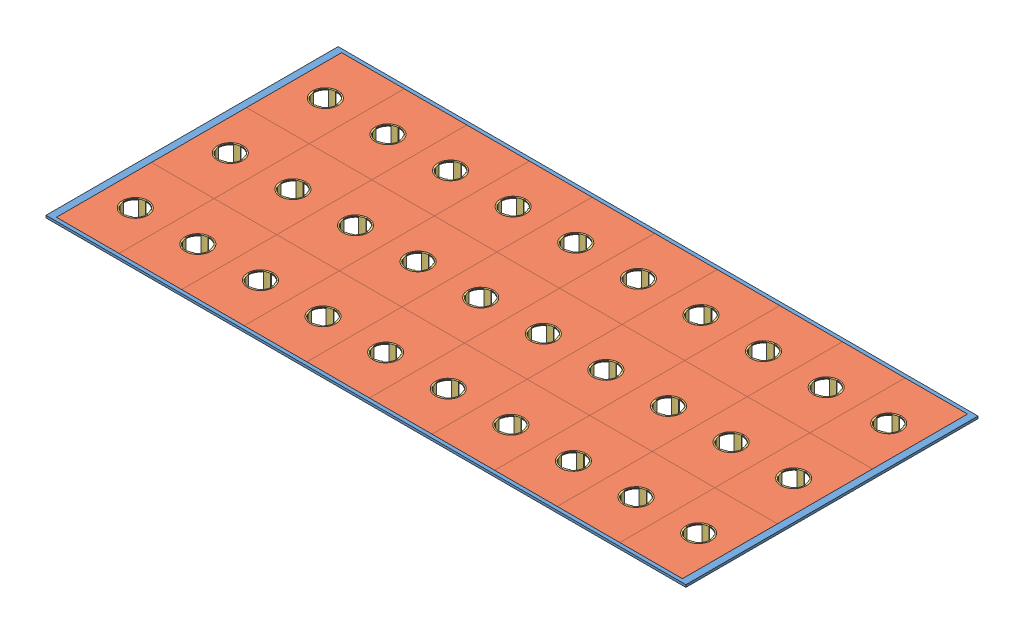
SolidWorks assembly A_Gaveta, configuration Default. Lengths in mm.
Overall size (1104 41 504.01).
61 component instances, 3 part files, 4 mates.
Components (placement in the parent):
- Estrutura_gaveta-2: Estrutura_gaveta [Default] at (152.42 973.7974 512.7504) size (1104 4 504.01)
- Copo_cultura-81: Copo_cultura [Default] at (-333.58 977.7974 348.7504) size (108 2 164)
- Copo_cultura-82: Copo_cultura [Default] at (-225.58 977.7974 348.7504) size (108 2 164)
- Copo_cultura-83: Copo_cultura [Default] at (-117.58 977.7974 348.7504) size (108 2 164)
- Copo_cultura-84: Copo_cultura [Default] at (-9.58 977.7974 348.7504) size (108 2 164)
- Copo_cultura-85: Copo_cultura [Default] at (98.42 977.7974 348.7504) size (108 2 164)
- Copo_cultura-86: Copo_cultura [Default] at (206.42 977.7974 348.7504) size (108 2 164)
- Copo_cultura-87: Copo_cultura [Default] at (314.42 977.7974 348.7504) size (108 2 164)
- Copo_cultura-88: Copo_cultura [Default] at (422.42 977.7974 348.7504) size (108 2 164)
- Copo_cultura-89: Copo_cultura [Default] at (530.42 977.7974 348.7504) size (108 2 164)
- Copo_cultura-90: Copo_cultura [Default] at (638.42 977.7974 348.7504) size (108 2 164)
- Copo_cultura-91: Copo_cultura [Default] at (-333.58 977.7974 512.7504) size (108 2 164)
- Copo_cultura-92: Copo_cultura [Default] at (-333.58 977.7974 676.7504) size (108 2 164)
- Copo_cultura-93: Copo_cultura [Default] at (-225.58 977.7974 512.7504) size (108 2 164)
- Copo_cultura-94: Copo_cultura [Default] at (-225.58 977.7974 676.7504) size (108 2 164)
- Copo_cultura-95: Copo_cultura [Default] at (-117.58 977.7974 512.7504) size (108 2 164)
- Copo_cultura-96: Copo_cultura [Default] at (-117.58 977.7974 676.7504) size (108 2 164)
- Copo_cultura-97: Copo_cultura [Default] at (-9.58 977.7974 512.7504) size (108 2 164)
- Copo_cultura-98: Copo_cultura [Default] at (-9.58 977.7974 676.7504) size (108 2 164)
- Copo_cultura-99: Copo_cultura [Default] at (98.42 977.7974 512.7504) size (108 2 164)
- Copo_cultura-100: Copo_cultura [Default] at (98.42 977.7974 676.7504) size (108 2 164)
- Copo_cultura-101: Copo_cultura [Default] at (206.42 977.7974 512.7504) size (108 2 164)
- Copo_cultura-102: Copo_cultura [Default] at (206.42 977.7974 676.7504) size (108 2 164)
- Copo_cultura-103: Copo_cultura [Default] at (314.42 977.7974 512.7504) size (108 2 164)
- Copo_cultura-104: Copo_cultura [Default] at (314.42 977.7974 676.7504) size (108 2 164)
- Copo_cultura-105: Copo_cultura [Default] at (422.42 977.7974 512.7504) size (108 2 164)
- Copo_cultura-106: Copo_cultura [Default] at (422.42 977.7974 676.7504) size (108 2 164)
- Copo_cultura-107: Copo_cultura [Default] at (530.42 977.7974 512.7504) size (108 2 164)
- Copo_cultura-108: Copo_cultura [Default] at (530.42 977.7974 676.7504) size (108 2 164)
- Copo_cultura-109: Copo_cultura [Default] at (638.42 977.7974 512.7504) size (108 2 164)
- Copo_cultura-110: Copo_cultura [Default] at (638.42 977.7974 676.7504) size (108 2 164)
- Capsula_Cultura-1: Capsula_Cultura [Default] at (-333.58 976.7974 676.7504) x (0.947711 0 -0.319129) z (0.319129 0 0.947711) size (44 41 44)
- Capsula_Cultura-2: Capsula_Cultura [Default] at (-225.58 976.7974 676.7504) x (0.947711 0 -0.319129) z (0.319129 0 0.947711) size (44 41 44)
- Capsula_Cultura-3: Capsula_Cultura [Default] at (-117.58 976.7974 676.7504) x (0.947711 0 -0.319129) z (0.319129 0 0.947711) size (44 41 44)
- Capsula_Cultura-4: Capsula_Cultura [Default] at (-9.58 976.7974 676.7504) x (0.947711 0 -0.319129) z (0.319129 0 0.947711) size (44 41 44)
- Capsula_Cultura-5: Capsula_Cultura [Default] at (98.42 976.7974 676.7504) x (0.947711 0 -0.319129) z (0.319129 0 0.947711) size (44 41 44)
- Capsula_Cultura-6: Capsula_Cultura [Default] at (206.42 976.7974 676.7504) x (0.947711 0 -0.319129) z (0.319129 0 0.947711) size (44 41 44)
- Capsula_Cultura-7: Capsula_Cultura [Default] at (314.42 976.7974 676.7504) x (0.947711 0 -0.319129) z (0.319129 0 0.947711) size (44 41 44)
- Capsula_Cultura-8: Capsula_Cultura [Default] at (422.42 976.7974 676.7504) x (0.947711 0 -0.319129) z (0.319129 0 0.947711) size (44 41 44)
- Capsula_Cultura-9: Capsula_Cultura [Default] at (530.42 976.7974 676.7504) x (0.947711 0 -0.319129) z (0.319129 0 0.947711) size (44 41 44)
- Capsula_Cultura-10: Capsula_Cultura [Default] at (638.42 976.7974 676.7504) x (0.947711 0 -0.319129) z (0.319129 0 0.947711) size (44 41 44)
- Capsula_Cultura-11: Capsula_Cultura [Default] at (-333.58 976.7974 512.7504) x (0.947711 0 -0.319129) z (0.319129 0 0.947711) size (44 41 44)
- Capsula_Cultura-12: Capsula_Cultura [Default] at (-333.58 976.7974 348.7504) x (0.947711 0 -0.319129) z (0.319129 0 0.947711) size (44 41 44)
- Capsula_Cultura-13: Capsula_Cultura [Default] at (-225.58 976.7974 512.7504) x (0.947711 0 -0.319129) z (0.319129 0 0.947711) size (44 41 44)
- Capsula_Cultura-14: Capsula_Cultura [Default] at (-225.58 976.7974 348.7504) x (0.947711 0 -0.319129) z (0.319129 0 0.947711) size (44 41 44)
- Capsula_Cultura-15: Capsula_Cultura [Default] at (-117.58 976.7974 512.7504) x (0.947711 0 -0.319129) z (0.319129 0 0.947711) size (44 41 44)
- Capsula_Cultura-16: Capsula_Cultura [Default] at (-117.58 976.7974 348.7504) x (0.947711 0 -0.319129) z (0.319129 0 0.947711) size (44 41 44)
- Capsula_Cultura-17: Capsula_Cultura [Default] at (-9.58 976.7974 512.7504) x (0.947711 0 -0.319129) z (0.319129 0 0.947711) size (44 41 44)
- Capsula_Cultura-18: Capsula_Cultura [Default] at (-9.58 976.7974 348.7504) x (0.947711 0 -0.319129) z (0.319129 0 0.947711) size (44 41 44)
- Capsula_Cultura-19: Capsula_Cultura [Default] at (98.42 976.7974 512.7504) x (0.947711 0 -0.319129) z (0.319129 0 0.947711) size (44 41 44)
- Capsula_Cultura-20: Capsula_Cultura [Default] at (98.42 976.7974 348.7504) x (0.947711 0 -0.319129) z (0.319129 0 0.947711) size (44 41 44)
- Capsula_Cultura-21: Capsula_Cultura [Default] at (206.42 976.7974 512.7504) x (0.947711 0 -0.319129) z (0.319129 0 0.947711) size (44 41 44)
- Capsula_Cultura-22: Capsula_Cultura [Default] at (206.42 976.7974 348.7504) x (0.947711 0 -0.319129) z (0.319129 0 0.947711) size (44 41 44)
- Capsula_Cultura-23: Capsula_Cultura [Default] at (314.42 976.7974 512.7504) x (0.947711 0 -0.319129) z (0.319129 0 0.947711) size (44 41 44)
- Capsula_Cultura-24: Capsula_Cultura [Default] at (314.42 976.7974 348.7504) x (0.947711 0 -0.319129) z (0.319129 0 0.947711) size (44 41 44)
- Capsula_Cultura-25: Capsula_Cultura [Default] at (422.42 976.7974 512.7504) x (0.947711 0 -0.319129) z (0.319129 0 0.947711) size (44 41 44)
- Capsula_Cultura-26: Capsula_Cultura [Default] at (422.42 976.7974 348.7504) x (0.947711 0 -0.319129) z (0.319129 0 0.947711) size (44 41 44)
- Capsula_Cultura-27: Capsula_Cultura [Default] at (530.42 976.7974 512.7504) x (0.947711 0 -0.319129) z (0.319129 0 0.947711) size (44 41 44)
- Capsula_Cultura-28: Capsula_Cultura [Default] at (530.42 976.7974 348.7504) x (0.947711 0 -0.319129) z (0.319129 0 0.947711) size (44 41 44)
- Capsula_Cultura-29: Capsula_Cultura [Default] at (638.42 976.7974 512.7504) x (0.947711 0 -0.319129) z (0.319129 0 0.947711) size (44 41 44)
- Capsula_Cultura-30: Capsula_Cultura [Default] at (638.42 976.7974 348.7504) x (0.947711 0 -0.319129) z (0.319129 0 0.947711) size (44 41 44)
Mates (geometry in assembly coordinates):
- Coincident4: coincident: line of Estrutura_gaveta-2 through (-387.58 977.7974 758.7504) axis (0 0 -1); line of Copo_cultura-81 through (-387.58 977.7974 266.7504) axis (0 0 1)
- Coincident5: coincident: plane of Estrutura_gaveta-2 through (-387.58 977.7974 266.7504) normal (0 0 1); line of Copo_cultura-81 through (-279.58 977.7974 266.7504) axis (-1 0 0)
- Coincident6: coincident: plane of Estrutura_gaveta-2 through (152.42 975.7974 512.7504) normal (0 1 0); plane of Copo_cultura-81 through (-333.58 975.7974 348.7504) normal (0 -1 0)
- Coincident7: coincident: circle of Copo_cultura-92; circle of Capsula_Cultura-1
